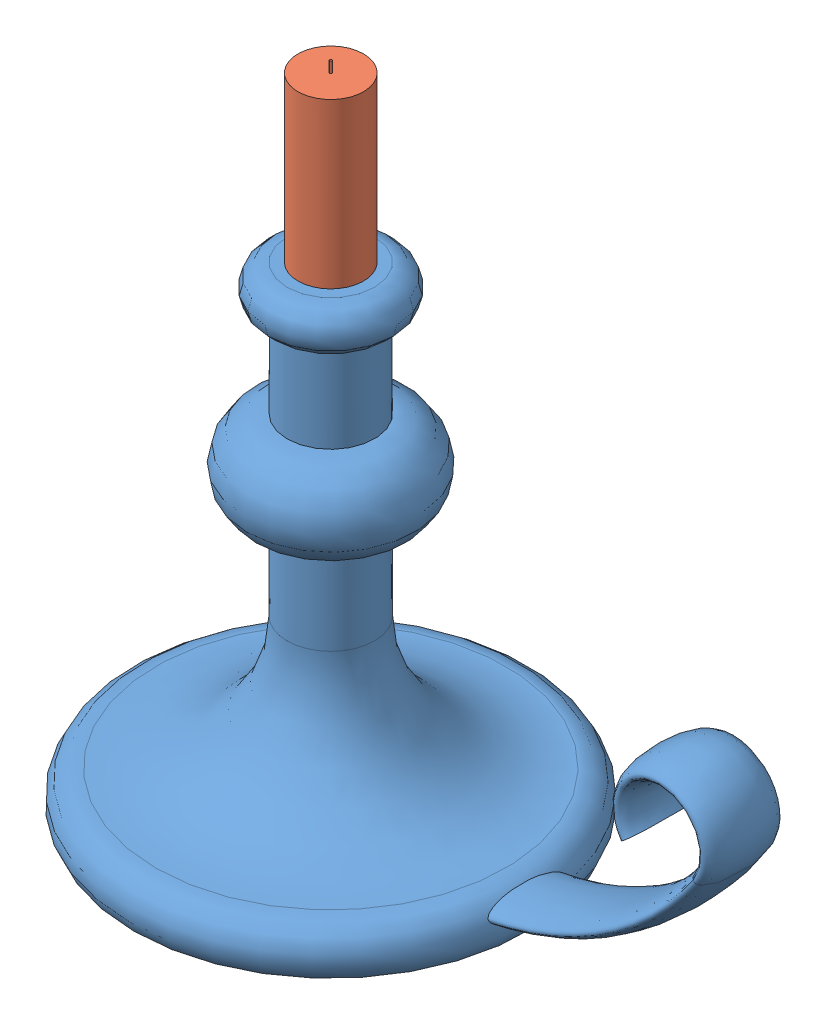
SolidWorks assembly Assem1, configuration Default. Lengths in mm.
Overall size (284.76 300 185).
2 component instances, 2 part files, 2 mates.
Components (placement in the parent):
- Part1-1: Part1 [Default] at (82.1462 32.0873 209.4255) size (284.76 220 185)
- Candle-1: Candle [Default] at (82.1462 227.0873 209.4255) size (30 105 30)
Mates (geometry in assembly coordinates):
- Coincident2: coincident anti-aligned: plane of Part1-1 through (82.1462 227.0873 209.4255) normal (0 1 0); plane of Candle-1 through (82.1462 227.0873 209.4255) normal (0 -1 0)
- Coincident4: coincident aligned: cone of Part1-1 through (82.1462 252.0873 209.4255) axis (0 -1 0); cone of Candle-1 through (82.1462 252.0873 209.4255) axis (0 -1 0)
